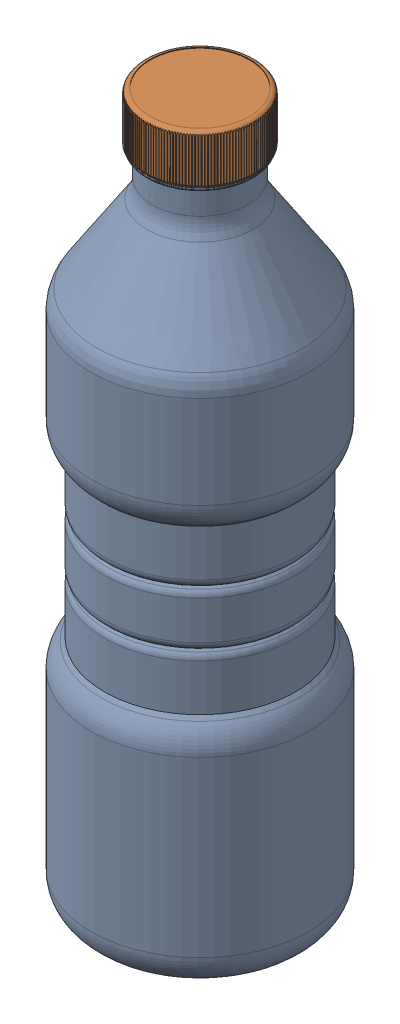
SolidWorks assembly Pet Bottle, configuration Default. Lengths in mm.
Overall size (64 208.89 64).
2 component instances, 2 part files, 3 mates.
Components (placement in the parent):
- Bottle-1: Bottle [Default] at (624.8764 -85.073 1058.2214) size (64 206.08 64)
- Bottle Cap-1: Bottle Cap [Default] at (624.8764 0.812 1058.2214) x (0.416275 0 0.909239) z (-0.909239 0 0.416275) size (32.16 14.4 32.16)
Mates (geometry in assembly coordinates):
- Concentric1: concentric aligned: circle of Bottle-1; circle of Bottle Cap-1
- Coincident2: coincident aligned: circle of Bottle-1
- Screw1: screw = 2 mm aligned: cylinder of Bottle-1 through (624.8764 0 1058.2214) axis (0 1 0) radius 14; axis of Bottle Cap-1 through (624.8764 -11.088 1058.2214) axis (0 1 0)
